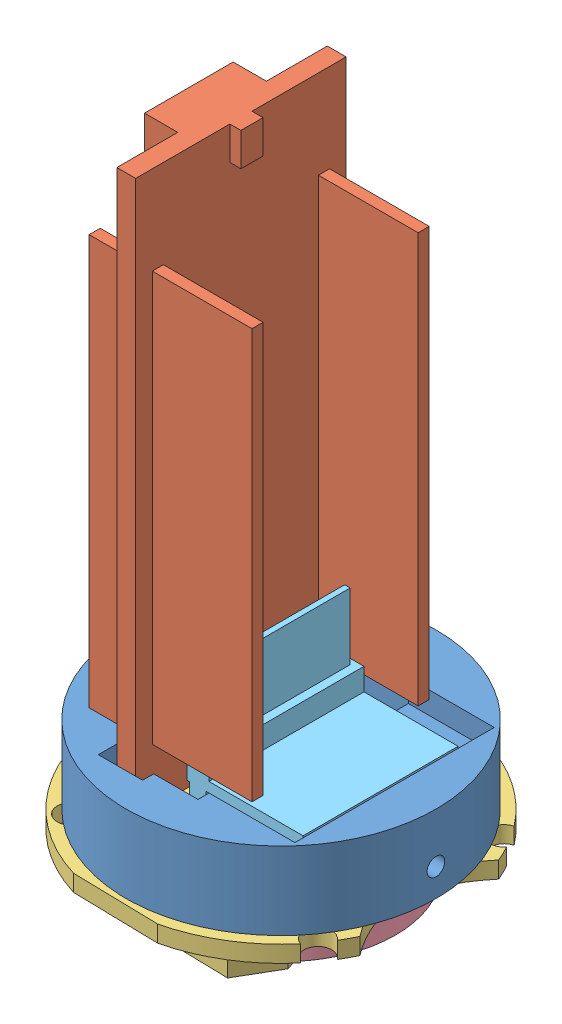
SolidWorks assembly Altimeter, configuration По умолчанию. Lengths in mm.
Overall size (29.34 56.95 29.63).
5 component instances, 5 part files, 2 mates.
Components (placement in the parent):
- Altimeter_Mount-1: Altimeter_Mount [По умолчанию] at origin size (28 7 28)
- STM32L031K6-1: STM32L031K6 [По умолчанию] at (-3.6258 27.2467 0) x (0 -1 0) z (0 0 -1) size (51 14.7 19)
- Battery_Mount-1: Battery_Mount [По умолчанию] at (0.9801 0 0.0031) x (-0.999752 0 -0.02229) z (-0.02229 0 0.999752) size (28.69 4.5 29)
- Battery_CR2032-1: Battery_CR2032 [По умолчанию] at (0.3246 -4.7 -0.0115) x (0.225986 0 -0.97413) z (0.97413 0 0.225986) size (20 3.2 20)
- BMP_280-1: BMP_280 [По умолчанию] at (3.7347 5.9 0) x (0 0 1) z (1 0 0) size (14 10.4 10.5)
Mates (geometry in assembly coordinates):
- Совпадение16: coordinate: point of Altimeter_Mount-1
- Совпадение24: coincident anti-aligned: plane of Altimeter_Mount-1 through (0 0 0) normal (0 -1 0); plane of Battery_Mount-1 through (0.9801 0 0.0031) normal (0 1 0)
